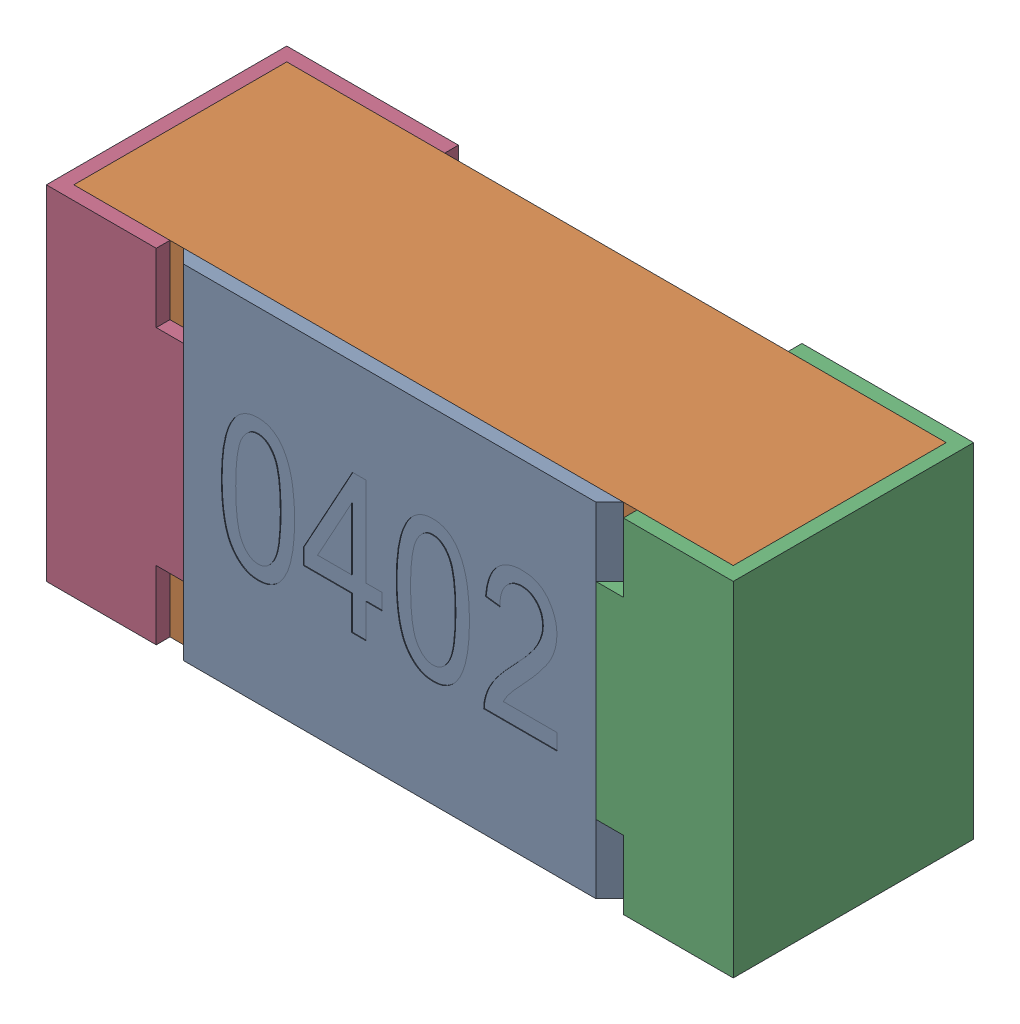
SolidWorks assembly R10, configuration Standard. Lengths in mm.
Overall size (1 0.5 0.35).
5 component instances, 4 part files, 0 mates.
Components (placement in the parent):
- R10-subassembly-1-1: R10-subassembly-1 [Standard] at (6.7001 -12.2 0) x (1 0 0) z (0 0 1) size (1 0.5 0.35)
  - User Library-R_0402-1: User Library-R_0402 [Standard] at origin size (0.64 0.5 0.02)
  - User Library-R_0402-1-1: User Library-R_0402-1 [Standard] at origin size (0.96 0.5 0.31)
  - User Library-R_0402-2-1: User Library-R_0402-2 [Standard] at origin size (0.25 0.5 0.35)
  - User Library-R_0402-3-1: User Library-R_0402-3 [Standard] at origin size (0.25 0.5 0.35)
